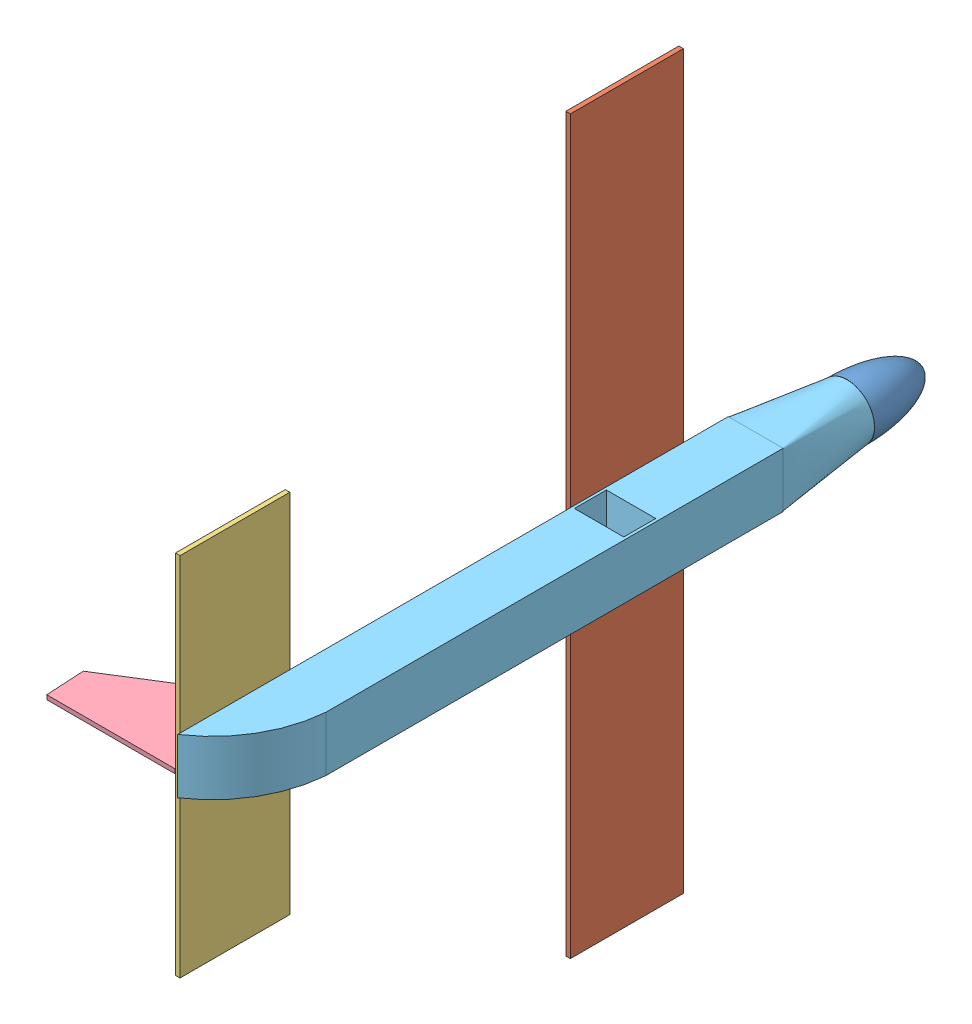
SolidWorks assembly Full_glider, configuration Default. Lengths in mm.
Overall size (262.92 1016 1069.76).
5 component instances, 5 part files, 5 mates.
Components (placement in the parent):
- Nose_cone-1: Nose_cone [Default] at (884.6005 519.6823 933.2678) x (0 0 -1) z (0.997563 0.06977 0) size (101.6 76.2 76.2)
- Glider_wing-4: Glider_wing [Default] at (840.1505 1031.4803 1228.9788) x (0 -1 0) z (0 0 1) size (1016 6.35 346.45)
- horizontal_stabilizer-3: horizontal_stabilizer [Default] at (840.1505 771.2427 1821.6052) x (0 -1 0) z (0 0 1) size (508 6.35 232.22)
- rear_elevator-3: rear_elevator [Default] at (840.1505 505.9876 1822.1995) x (0 0.998201 0.059959) z (0 -0.059959 0.998201) size (6.35 177.8 152.4)
- fuselage_2-1: fuselage_2 [Default] at (926.578 481.5823 1753.1095) x (0 0 -1) z (0 1 0) size (891.54 76.2 76.2)
Mates (geometry in assembly coordinates):
- Coincident24: coincident anti-aligned: plane of horizontal_stabilizer-3 through (840.1505 771.2427 1821.6052) normal (-1 0 0); plane of rear_elevator-3 through (840.1505 512.3261 1822.5803) normal (1 0 0)
- ProfileCenter1: profile center anti-aligned: plane of Nose_cone-1 through (881.9422 557.6894 933.2678) normal (0 0 1); plane of fuselage_2-1 through (858.3395 547.139 933.2678) normal (0 0 -1)
- Coincident34: coincident anti-aligned: plane of Glider_wing-4 through (846.5005 1031.4803 1228.9788) normal (1 0 0); plane of fuselage_2-1 through (846.5005 557.7823 1824.8078) normal (-1 0 0)
- Coincident35: coincident anti-aligned: plane of horizontal_stabilizer-3 through (846.5005 771.2427 1821.6052) normal (1 0 0); plane of fuselage_2-1 through (846.5005 557.7823 1824.8078) normal (-1 0 0)
- Coincident37: coincident anti-aligned: plane of horizontal_stabilizer-3 through (840.1505 771.2427 1821.6052) normal (-1 0 0); plane of rear_elevator-3 through (840.1505 512.3261 1822.5803) normal (1 0 0)
